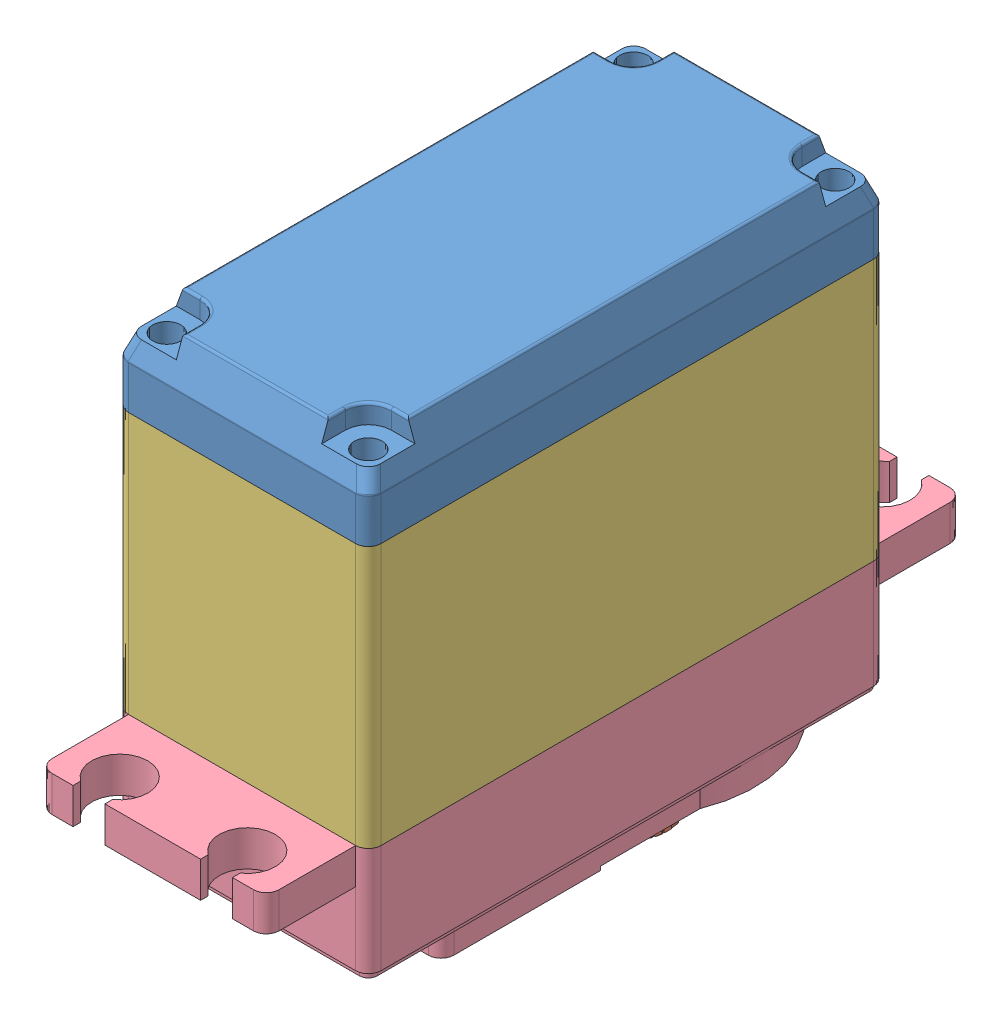
SolidWorks assembly MG_996R, configuration Domyślna. Lengths in mm.
Overall size (19.93 44.4 54.6).
4 component instances, 4 part files, 8 mates.
Components (placement in the parent):
- Base-1: Base [Domyślna] at (12.6939 -23.8049 -20.4733) size (19.93 6.4 40.73)
- Eje-1: Eje [Domyślna] at (12.6939 -50.7049 -30.7733) x (-0.837169 0 -0.546944) z (-0.546944 0 0.837169) size (5.78 17.5 5.8)
- Medio-1: Medio [Domyślna] at (12.6939 -30.2049 -20.4733) size (19.8 20.5 40.6)
- Top-1: Top [Domyślna] at (12.6939 -59.7049 -20.4733) x (-1 0 0) z (0 0 1) size (19.8 13.2 54.6)
Mates (geometry in assembly coordinates):
- Wspólnie2: coincident aligned: plane of Base-1 through (22.5939 -23.8049 -40.7733) normal (1 0 0); plane of Medio-1 through (22.5939 -30.2049 -40.7733) normal (1 0 0)
- Wspólnie5: coincident anti-aligned: plane of Base-1 through (12.6939 -30.2049 -20.4733) normal (0 -1 0); plane of Medio-1 through (12.6939 -30.2049 -20.4733) normal (0 1 0)
- Wspólnie6: coincident aligned: plane of Base-1 through (22.5939 -23.8049 -0.1733) normal (0 0 1); plane of Medio-1 through (22.5939 -30.2049 -0.1733) normal (0 0 1)
- Wspólnie7: coincident anti-aligned: plane of Medio-1 through (12.6939 -50.7049 -20.4733) normal (0 -1 0); plane of Top-1 through (12.6939 -50.7049 -20.4733) normal (0 1 0)
- Wspólnie8: coincident aligned: plane of Medio-1 through (22.5939 -30.2049 -40.7733) normal (1 0 0); plane of Top-1 through (22.5939 -59.7049 -0.1733) normal (1 0 0)
- Wspólnie9: coincident aligned: plane of Medio-1 through (2.7939 -30.2049 -40.7733) normal (0 0 -1); plane of Top-1 through (22.5939 -59.7049 -40.7733) normal (0 0 -1)
- Koncentryczne1: concentric anti-aligned: cylinder of Eje-1 through (12.6939 -50.7049 -30.7733) axis (0 1 0) radius 2.65; cylinder of Top-1 through (12.6939 -59.7049 -30.7733) axis (0 -1 0) radius 3
- Wspólnie11: coincident anti-aligned: plane of Eje-1 through (12.6939 -50.7049 -30.7733) normal (0 1 0); plane of Medio-1 through (12.6939 -50.7049 -20.4733) normal (0 -1 0)
